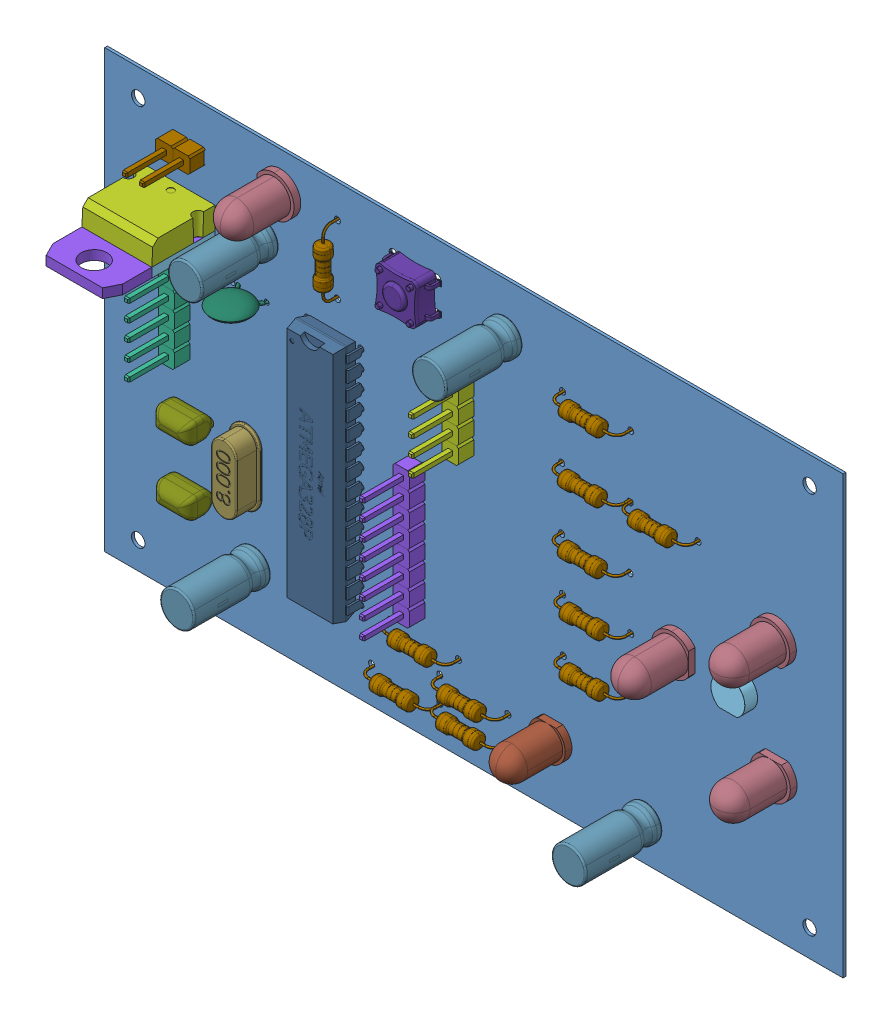
SolidWorks assembly pcb f, configuration Default. Lengths in mm.
Overall size (109.98 65.02 18.03).
67 component instances, 27 part files, 0 mates.
Components (placement in the parent):
- pcb f.step-1: pcb f.step [Default] at origin size (109.98 65.02 48.99)
  - Board.step-1: Board.step [Default] at origin size (109.98 65.02 0.41)
    - Open CASCADE STEP translator 6.8 1.1.1.step-1: Open CASCADE STEP translator 6.8 1.1.1.step [Default] at (0 0 -0.4115) size (109.98 65.02 0.41)
  - Free-Models.step-1: Free-Models.step [Default] at origin size (96.92 59.5 48.99)
    - LDR_cell_thru-hole_leaded.step-1: LDR_cell_thru-hole_leaded.step [Default] at (133.223 68.199 2) x (0 1 0) z (1 0 0) size (4.25 35.23 5.05)
      - Ceramic_base^LDR_cell_thru-hole_leaded.step-1: Ceramic_base^LDR_cell_thru-hole_leaded.step [Default] x (1 0 0) z (0 1 0) size (4.2 5 1.7)
      - Electrodes^LDR_cell_thru-hole_leaded.step-1: Electrodes^LDR_cell_thru-hole_leaded.step [Default] x (1 0 0) z (0 1 0) size (4 4.8 0.05)
      - Leads^LDR_cell_thru-hole_leaded.step-1: Leads^LDR_cell_thru-hole_leaded.step [Default] x (1 0 0) z (0 1 0) size (0.65 4.05 35.2)
      - Part16^LDR_cell_thru-hole_leaded.step-1: Part16^LDR_cell_thru-hole_leaded.step [Default] x (1 0 0) z (0 1 0) size (4.25 5.05 1.9)
    - 5x_Male_Pin_2.54_mm.step-1: 5x_Male_Pin_2.54_mm.step [Default] at (38.5793 76.5707 -5) x (0 1 0) z (1 0 0) size (12.7 11.1 2.4)
      - 1_Male_Pin_2.54_mm.step-1: 1_Male_Pin_2.54_mm.step [Default] at (3.8763 2.2562 11.0637) size (2.54 11.1 2.4)
      - 1_Male_Pin_2.54_mm.step-2: 1_Male_Pin_2.54_mm.step [Default] at (1.3363 2.2562 11.0637) size (2.54 11.1 2.4)
      - 1_Male_Pin_2.54_mm.step-3: 1_Male_Pin_2.54_mm.step [Default] at (-1.2037 2.2562 11.0637) size (2.54 11.1 2.4)
      - 1_Male_Pin_2.54_mm.step-4: 1_Male_Pin_2.54_mm.step [Default] at (-3.7437 2.2562 11.0637) size (2.54 11.1 2.4)
      - 1_Male_Pin_2.54_mm.step-5: 1_Male_Pin_2.54_mm.step [Default] at (-6.2837 2.2562 11.0637) size (2.54 11.1 2.4)
    - 4x_Male_Pin_2.54_mm.step-1: 4x_Male_Pin_2.54_mm.step [Default] at (80.8703 82.7937 -5) x (0 1 0) z (1 0 0) size (10.16 11.1 2.4)
      - 1_Male_Pin_2.54_mm-0.step-1: 1_Male_Pin_2.54_mm-0.step [Default] at (3.8763 2.2562 11.0637) size (2.54 11.1 2.4)
      - 1_Male_Pin_2.54_mm-0.step-2: 1_Male_Pin_2.54_mm-0.step [Default] at (1.3363 2.2562 11.0637) size (2.54 11.1 2.4)
      - 1_Male_Pin_2.54_mm-0.step-3: 1_Male_Pin_2.54_mm-0.step [Default] at (-1.2037 2.2562 11.0637) size (2.54 11.1 2.4)
      - 1_Male_Pin_2.54_mm-0.step-4: 1_Male_Pin_2.54_mm-0.step [Default] at (-3.7437 2.2562 11.0637) size (2.54 11.1 2.4)
    - 8x_Male_Pin_2.54_mm.step-1: 8x_Male_Pin_2.54_mm.step [Default] at (73.5743 68.3157 -5) x (0 1 0) z (1 0 0) size (20.32 11.1 2.4)
      - 1_Male_Pin_2.54_mm-1.step-1: 1_Male_Pin_2.54_mm-1.step [Default] at (3.8763 2.2562 11.0637) size (2.54 11.1 2.4)
      - 1_Male_Pin_2.54_mm-1.step-2: 1_Male_Pin_2.54_mm-1.step [Default] at (1.3363 2.2562 11.0637) size (2.54 11.1 2.4)
      - 1_Male_Pin_2.54_mm-1.step-3: 1_Male_Pin_2.54_mm-1.step [Default] at (-1.2037 2.2562 11.0637) size (2.54 11.1 2.4)
      - 1_Male_Pin_2.54_mm-1.step-4: 1_Male_Pin_2.54_mm-1.step [Default] at (-3.7437 2.2562 11.0637) size (2.54 11.1 2.4)
      - 1_Male_Pin_2.54_mm-1.step-5: 1_Male_Pin_2.54_mm-1.step [Default] at (-6.2837 2.2562 11.0637) size (2.54 11.1 2.4)
      - 1_Male_Pin_2.54_mm-1.step-6: 1_Male_Pin_2.54_mm-1.step [Default] at (-8.8237 2.2562 11.0637) size (2.54 11.1 2.4)
      - 1_Male_Pin_2.54_mm-1.step-7: 1_Male_Pin_2.54_mm-1.step [Default] at (-11.3637 2.2562 11.0637) size (2.54 11.1 2.4)
      - 1_Male_Pin_2.54_mm-1.step-8: 1_Male_Pin_2.54_mm-1.step [Default] at (-13.9037 2.2562 11.0637) size (2.54 11.1 2.4)
    - 2x_Male_Pin_2.54_mm.step-1: 2x_Male_Pin_2.54_mm.step [Default] at (47.9957 108.2327 -5) x (1 0 0) z (0 -1 0) size (5.08 11.1 2.4)
      - 1_Male_Pin_2.54_mm-2.step-1: 1_Male_Pin_2.54_mm-2.step [Default] at (3.8763 2.2562 11.0637) size (2.54 11.1 2.4)
      - 1_Male_Pin_2.54_mm-2.step-2: 1_Male_Pin_2.54_mm-2.step [Default] at (1.3363 2.2562 11.0637) size (2.54 11.1 2.4)
    - ATMEGA328p.step-1: ATMEGA328p.step [Default] at (68.487 83.486 0) x (1 0 0) z (0 0 1) size (8.13 35.4 6.99)
    - CA_GRB_LED_5mm.step-1: CA_GRB_LED_5mm.step [Default] at (105.073 47.663 0) x (0 1 0) z (1 0 0) size (5.12 34.2 5.5)
    - crystal_oscillator.step-1: crystal_oscillator.step [Default] at (59.436 59.944 0) x (0 1 0) z (1 0 0) size (11.05 6.5 4.65)
    - LED_GREEN_5MM.step-1: LED_GREEN_5MM.step [Default] at (64.437 97.711 9) x (0 -1 0) z (0 0 -1) size (6 5.5 14)
    - LED_GREEN_5MM.step-2: LED_GREEN_5MM.step [Default] at (123.65 68.151 9) x (0 1 0) z (0 0 -1) size (6 5.5 14)
    - LED_GREEN_5MM.step-3: LED_GREEN_5MM.step [Default] at (138.351 59.559 9) x (-1 0 0) z (0 0 -1) size (6 5.5 14)
    - LED_GREEN_5MM.step-4: LED_GREEN_5MM.step [Default] at (138.255 76.966 9) x (1 0 0) z (0 0 -1) size (6 5.5 14)
    - 100uF.step-1: 100uF.step [Default] at (60.452 47.5928 0) x (1 0 0) z (0 -1 0) size (5.15 17.45 5.15)
    - 100uF.step-2: 100uF.step [Default] at (61.63 90.5188 0) x (1 0 0) z (0 -1 0) size (5.15 17.45 5.15)
    - 100uF.step-3: 100uF.step [Default] at (97.952 95.9799 0) x (1 0 0) z (0 -1 0) size (5.15 17.45 5.15)
    - 100uF.step-4: 100uF.step [Default] at (118.78 43.7828 0) x (1 0 0) z (0 -1 0) size (5.15 17.45 5.15)
    - disccap.step-1: disccap.step [Default] at (59.9786 82.3645 3) x (1 0 0) z (0 0 -1) size (6.01 2.04 31)
    - RDER71H105K2M1C03A.step-1: RDER71H105K2M1C03A.step [Default] at (51.8051 53.1552 2) x (1 0 0) z (0 -1 0) size (5.6 19.97 3.35)
    - RDER71H105K2M1C03A.step-2: RDER71H105K2M1C03A.step [Default] at (51.733 62.789 2) x (1 0 0) z (0 -1 0) size (5.6 19.97 3.35)
    - Push_Button_Tactile.step-1: Push_Button_Tactile.step [Default] at (84.582 95.885 0) x (1 0 0) z (0 -1 0) size (7.66 3.5 6)
    - regulator.step-1: regulator.step [Default] at (49.6496 86.639 5) x (-1 0 0) z (0 1 0) size (10.43 0.01 1.4)
    - regulator-3.step-1: regulator-3.step [Default] at (49.6496 86.639 5) x (-1 0 0) z (0 1 0) size (1.7 14 0.7)
    - regulator-4.step-1: regulator-4.step [Default] at (49.6496 86.639 5) x (-1 0 0) z (0 1 0) size (1.7 14 0.7)
    - regulator-5.step-1: regulator-5.step [Default] at (49.6496 86.639 5) x (-1 0 0) z (0 1 0) size (1.7 14 0.7)
    - regulator-6.step-1: regulator-6.step [Default] at (49.6496 86.639 5) x (-1 0 0) z (0 1 0) size (10.4 9.42 0.03)
    - regulator-7.step-1: regulator-7.step [Default] at (49.6496 86.639 5) x (-1 0 0) z (0 1 0) size (0.01 9.42 1.4)
    - regulator-8.step-1: regulator-8.step [Default] at (49.6496 86.639 5) x (-1 0 0) z (0 1 0) size (0.01 9.42 1.4)
    - regulator-9.step-1: regulator-9.step [Default] at (49.6496 86.639 5) x (-1 0 0) z (0 1 0) size (10.43 9.44 3.3)
    - regulator-10.step-1: regulator-10.step [Default] at (49.6496 86.639 5) x (-1 0 0) z (0 1 0) size (10.4 15.75 1.4)
    - axial_resistor_6mm.step-1: axial_resistor_6mm.step [Default] at (111.506 93.023 2) x (1 0 0) z (0 -1 0) size (10.3 5.14 2.15)
    - axial_resistor_6mm.step-2: axial_resistor_6mm.step [Default] at (93.345 47.244 2) x (1 0 0) z (0 -1 0) size (10.3 5.14 2.15)
    - axial_resistor_6mm.step-3: axial_resistor_6mm.step [Default] at (85.979 50.673 2) x (1 0 0) z (0 -1 0) size (10.3 5.14 2.15)
    - axial_resistor_6mm.step-4: axial_resistor_6mm.step [Default] at (83.312 43.561 2) x (1 0 0) z (0 -1 0) size (10.3 5.14 2.15)
    - axial_resistor_6mm.step-5: axial_resistor_6mm.step [Default] at (111.633 59.114 2) x (1 0 0) z (0 -1 0) size (10.3 5.14 2.15)
    - axial_resistor_6mm.step-6: axial_resistor_6mm.step [Default] at (93.218 43.561 2) x (1 0 0) z (0 -1 0) size (10.3 5.14 2.15)
    - axial_resistor_6mm.step-7: axial_resistor_6mm.step [Default] at (72.771 93.345 2) x (0 1 0) z (1 0 0) size (10.3 5.14 2.15)
    - axial_resistor_6mm.step-8: axial_resistor_6mm.step [Default] at (111.633 66.929 2) x (1 0 0) z (0 -1 0) size (10.3 5.14 2.15)
    - axial_resistor_6mm.step-9: axial_resistor_6mm.step [Default] at (121.793 84.006 2) x (1 0 0) z (0 -1 0) size (10.3 5.14 2.15)
    - axial_resistor_6mm.step-10: axial_resistor_6mm.step [Default] at (111.379 74.803 2) x (1 0 0) z (0 -1 0) size (10.3 5.14 2.15)
    - axial_resistor_6mm.step-11: axial_resistor_6mm.step [Default] at (111.379 83.947 2) x (1 0 0) z (0 -1 0) size (10.3 5.14 2.15)
